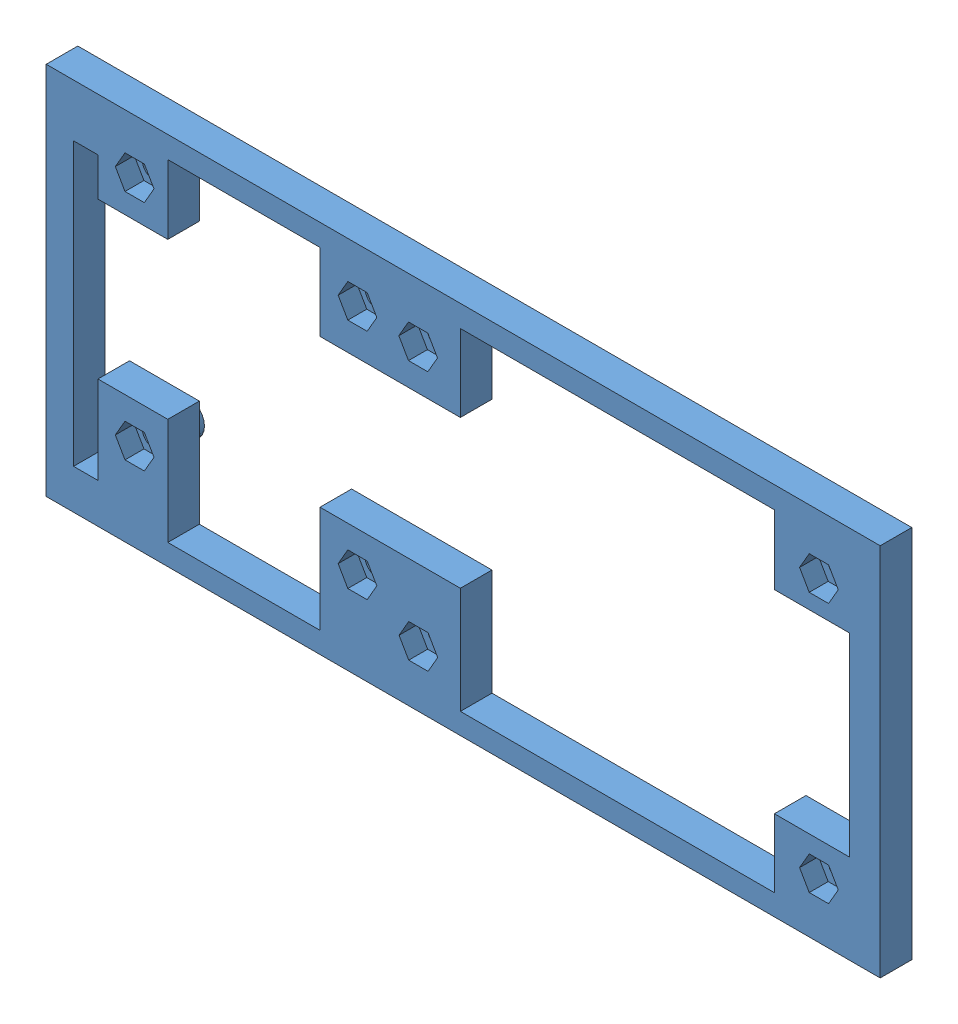
SolidWorks assembly Assem1, configuration Default. Lengths in mm.
Overall size (132 108 30.75).
3 component instances, 3 part files, 5 mates.
Components (placement in the parent):
- board-1: board [Default] at (-35.2387 69.1477 66.5921) size (72 49.25 2) (hidden)
- Part2^Assem1-1: Part2^Assem1 [Default] at (-35.2387 69.1477 66.5921) x (-1 0 0) z (0 0 -1) size (132 108 30.75) (virtual)
- shield_puente_h_L298N-1: shield_puente_h_L298N [Default] at (-112.6602 45.0457 66.0921) x (-0.004475 0.99999 0) z (0 0 1) size (44.6 44.6 28.1) (hidden)
Mates (geometry in assembly coordinates):
- InPlace1: in place: plane of board-1 through (-35.2387 69.1477 66.5921) normal (0 0 -1); plane of ? through (0 0 66.5921) normal (0 0 -1); moOrthogonalPlaneRef_w of board-1 through (-35.2387 69.1477 66.5921) normal (0 0 -1); plane of ? through (0 0 66.5921) normal (0 1 0); plane of board-1 through (-35.2387 69.1477 66.5921) normal (0 0 -1); plane of ? through (0 0 66.5921) normal (-1 0 0); plane of board-1 through (-35.2387 69.1477 66.5921) normal (0 0 -1); unknown of Part2^Assem1-1
- Coincident1: coincident aligned: plane of board-1; plane of Part2^Assem1-1
- Coincident2: coincident aligned: moOrthogonalPlaneRef_w of board-1 through (-35.2387 69.1477 66.5921) normal (0 1 0); plane of Part2^Assem1-1 through (-35.2387 69.1477 66.5921) normal (0 1 0)
- Coincident3: coincident anti-aligned: moOrthogonalPlaneRef_w of board-1 through (-35.2387 69.1477 66.5921) normal (1 0 0); plane of Part2^Assem1-1 through (-35.2387 69.1477 66.5921) normal (-1 0 0)
- Coincident5: coincident anti-aligned: plane of Part2^Assem1-1 through (-35.2387 69.1477 66.0921) normal (0 0 1); plane of shield_puente_h_L298N-1 through (-112.6602 45.0457 66.0921) normal (0 0 -1)
